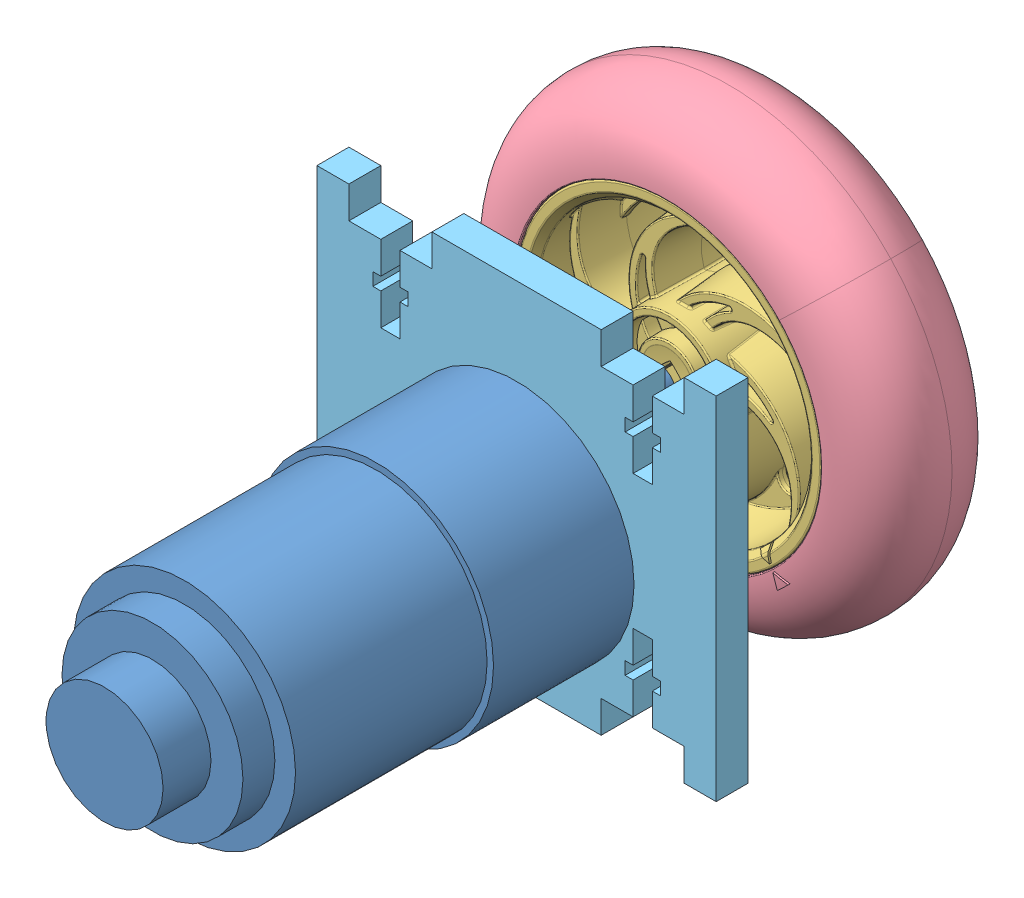
SolidWorks assembly WheelAssembly, configuration Default. Lengths in mm.
Overall size (98.76 98.76 107.94).
6 component instances, 5 part files, 8 mates.
Components (placement in the parent):
- gearnotor_w_encoder-1: gearnotor_w_encoder [Default] x (1 0 0) z (0 0 -1) size (36.8 36.8 86.5)
- VEX-SMALL-WHEEL-1: VEX-SMALL-WHEEL [Default] at (0.1988 28.8062 -57.9151) x (0.725509 0.688213 0) z (0 0 -1) size (69.86 69.86 20.66)
  - SMALL-WHEEL-RIM-1: SMALL-WHEEL-RIM [Default] at (-15.1515 15.6838 -2.6601) size (61.43 61.43 9.24)
  - SMALL-WHEEL-HUB-1: SMALL-WHEEL-HUB [Default] at (-15.1515 15.6838 -2.6601) size (61.36 61.43 20.66)
  - SMALL-WHEEL-TIRE-1: SMALL-WHEEL-TIRE [Default] at (-15.1515 15.6838 -2.6601) x (1 0 0) z (0 -1 0) size (69.86 19.99 69.86)
- motor_mount-1: motor_mount [Default] at (0 0 -22) x (1 0 0) z (0 0 -1) size (62.5 60 5)
Mates (geometry in assembly coordinates):
- Concentric1: concentric anti-aligned: cylinder of gearnotor_w_encoder-1 through (0 7 -44) axis (0 0 1) radius 3; cone of VEX-SMALL-WHEEL-1/SMALL-WHEEL-HUB-1 through (0 7 -55.255) axis (0 0 -1)
- Distance1: distance = 2 mm anti-aligned: moEndPointRef_w of VEX-SMALL-WHEEL-1/SMALL-WHEEL-HUB-1; plane of gearnotor_w_encoder-1 through (0 7 -44) normal (0 0 -1)
- Coincident1: coincident anti-aligned: plane of gearnotor_w_encoder-1 through (0 0 -22) normal (0 0 -1); plane of motor_mount-1 through (-27.5 -23 -22) normal (0 0 1)
- Concentric5: concentric aligned: cylinder of gearnotor_w_encoder-1 through (0 7 -28.5) axis (0 0 1) radius 6; cylinder of motor_mount-1 through (0 7 -27) axis (0 0 1) radius 6
- Coincident2: coincident aligned: plane of gearnotor_w_encoder-1; plane of assembly through (0 0 0) normal (1 0 0)
- Coincident3: coincident anti-aligned: plane of gearnotor_w_encoder-1 through (0 0 0) normal (0 -1 0); plane of assembly through (0 0 0) normal (0 1 0)
- Coincident4: coincident anti-aligned: plane of gearnotor_w_encoder-1 through (0 0 0) normal (0 0 -1); plane of assembly through (0 0 0) normal (0 0 1)
- Concentric9: concentric anti-aligned: cylinder of gearnotor_w_encoder-1 through (15.5 0 -17) axis (0 0 -1) radius 1.5; cylinder of motor_mount-1 through (15.5 0 -27) axis (0 0 1) radius 1.5
